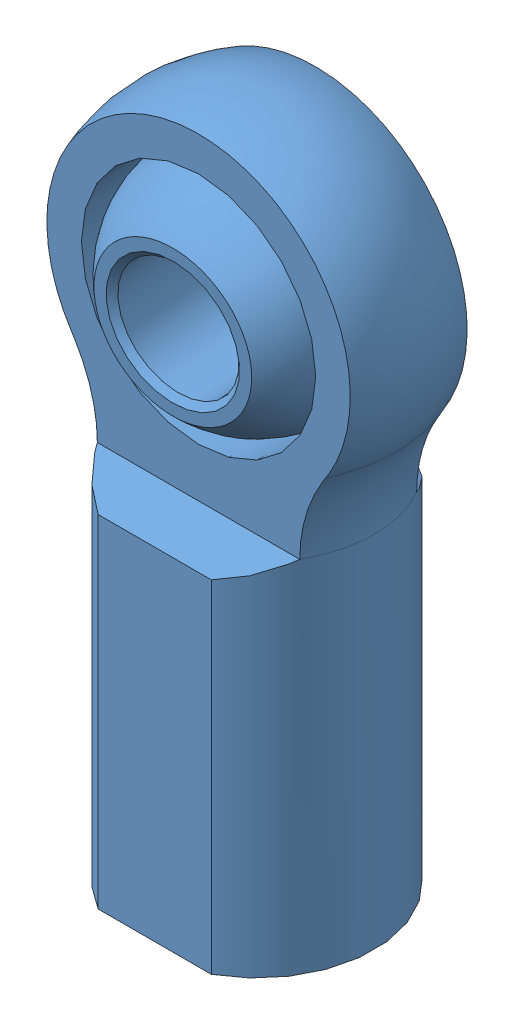
SolidWorks assembly 59935K73 - Ball Joint Rod End, configuration Default. Lengths in mm.
Overall size (22.45 47.25 22.25).
2 component instances, 1 part files, 2 mates.
Components (placement in the parent):
- 59935K73 - Ball Joint Rod End-1: 59935K73 - Ball Joint Rod End [Rod End] at (-48.2619 34.0569 10.7792) size (22.25 47.12 22.25)
- 59935K73 - Ball Joint Rod End-2: 59935K73 - Ball Joint Rod End [Ball] at (-48.2619 34.0569 10.7792) x (0.525036 0.850931 0.015934) z (0.038179 -0.042252 0.998377) size (15.88 15.88 15.88)
Mates (geometry in assembly coordinates):
- Coincident1: coincident: point of 59935K73 - Ball Joint Rod End-1; point of 59935K73 - Ball Joint Rod End-2
- LimitAngle1: limit planar angle = 0.056977 rad aligned: cylinder of 59935K73 - Ball Joint Rod End-2 through (-48.5292 34.3527 3.7906) axis (0.038179 -0.042252 0.998377) radius 4; cylinder of 59935K73 - Ball Joint Rod End-1 through (-48.2619 34.0569 3.7792) axis (0 0 1) radius 8.0194
